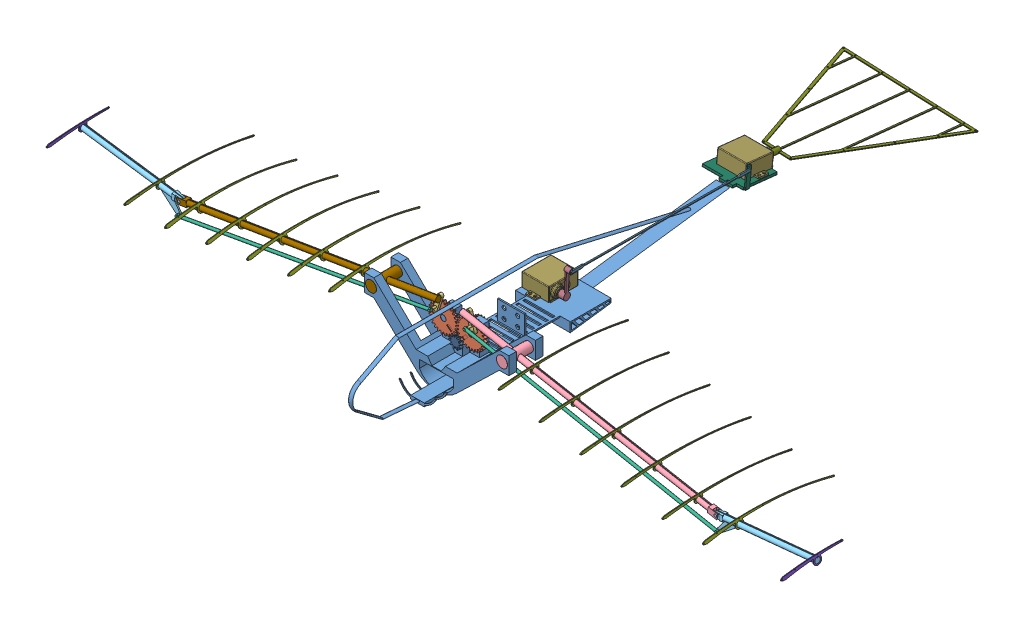
SolidWorks assembly 仿生扑翼鸟, configuration 默认. Lengths in mm.
Overall size (541.74 54.34 414.7).
33 component instances, 16 part files, 88 mates.
Components (placement in the parent):
- 驱干-1: 驱干 [默认] at origin size (106 50.33 280.63)
- 大齿轮-1: 大齿轮 [默认] at (10 25 8.1) x (0 0 1) z (-0.72003 0.693943 0) size (4.5 21.54 21.58)
- 连杆（齿轮-大翼）-1: 连杆（齿轮-大翼） [默认] at (13.8167 28.9602 10.6) x (0.265684 -0.96406 0) z (0 0 1) size (15 3 7.5)
- 大翼-右-1: 大翼-右 [默认] at (8.6616 40.8911 15.1) x (0.983461 -0.181119 0) z (0 0 1) size (192.4 8 25.2)
- 小翼-1: 小翼 [默认] at (269.4548 13.4698 15.1) x (0.995238 0.09747 0) z (0 0 1) size (75.4 13.5 4)
- 小翼连接件-1: 小翼连接件 [默认] at (197.379 -3.6369 17.6) x (-0.981244 0.192772 0) z (0 0 1) size (190 2 3)
- 大叶片-1: 大叶片 [默认] at (62.3222 32.7373 40.1) x (0 0 -1) z (0.983461 -0.181119 0) size (96.21 9.07 0.5)
- 大叶片-2: 大叶片 [默认] at (92.3178 27.2132 40.1) x (0 0 -1) z (0.983461 -0.181119 0) size (96.21 9.07 0.5)
- 大叶片-3: 大叶片 [默认] at (122.3134 21.689 40.1) x (0 0 -1) z (0.983461 -0.181119 0) size (96.21 9.07 0.5)
- 大叶片-4: 大叶片 [默认] at (152.3089 16.1649 40.1) x (0 0 -1) z (0.983461 -0.181119 0) size (96.21 9.07 0.5)
- 大叶片-6: 大叶片 [默认] at (182.3045 10.6408 40.1) x (0 0 -1) z (0.983461 -0.181119 0) size (96.21 9.07 0.5)
- 大叶片-9: 大叶片 [默认] at (211.8141 9.5328 40.1) x (0 0 -1) z (0.995238 0.09747 0) size (96.21 9.07 0.5)
- 小叶片-1: 小叶片 [默认] at (269.0403 15.1373 40.1) x (0 0 -1) z (0.995238 0.09747 0) size (45.94 7.58 0.6)
- 大翼-左-1: 大翼-左 [默认] at (-8.5358 40.1717 15.1) x (0.986604 0.163134 0) z (0 0 1) size (192.4 8 25.2)
- 大齿轮-2: 大齿轮 [默认] at (-10 25 8.1) x (0 0 1) z (-0.627917 -0.77828 0) size (4.5 21.54 21.58)
- 连杆（齿轮-大翼）-2: 连杆（齿轮-大翼） [默认] at (-14.2805 28.4535 10.6) x (-0.314291 -0.949327 0) z (0 0 1) size (15 3 7.5)
- 小翼-2: 小翼 [默认] at (-269.5532 19.3224 15.1) x (-0.990119 0.140232 0) z (0 0 -1) size (75.4 13.5 4)
- 小翼连接件-2: 小翼连接件 [默认] at (-198.2808 -0.8718 17.6) x (0.984554 0.175081 0) z (0 0 1) size (190 2 3)
- 大叶片-10: 大叶片 [默认] at (-62.3364 32.9989 40.1) x (0 0 -1) z (0.986604 0.163134 0) size (96.21 9.07 0.5)
- 大叶片-11: 大叶片 [默认] at (-92.4279 28.0233 40.1) x (0 0 -1) z (0.986604 0.163134 0) size (96.21 9.07 0.5)
- 大叶片-12: 大叶片 [默认] at (-122.5193 23.0477 40.1) x (0 0 -1) z (0.986604 0.163134 0) size (96.21 9.07 0.5)
- 大叶片-13: 大叶片 [默认] at (-152.6107 18.0721 40.1) x (0 0 -1) z (0.986604 0.163134 0) size (96.21 9.07 0.5)
- 大叶片-14: 大叶片 [默认] at (-182.7021 13.0965 40.1) x (0 0 -1) z (0.986604 0.163134 0) size (96.21 9.07 0.5)
- 大叶片-16: 大叶片 [默认] at (-212.1355 12.9072 40.1) x (0 0 -1) z (0.990119 -0.140232 0) size (96.21 9.07 0.5)
- 小叶片-2: 小叶片 [默认] at (-269.0673 20.9706 40.1) x (0 0 -1) z (0.990119 -0.140232 0) size (45.94 7.58 0.6)
- 小齿轮-1: 小齿轮 [默认] at (-1.4647 14 8.1) x (0 0 1) z (-0.996806 -0.079858 0) size (20 9.19 9.6)
- 中齿轮-1: 中齿轮 [默认] at (-1.4647 14 -9.9) x (0 0 1) z (0.760364 -0.649497 0) size (1.6 13.95 13.95)
- 伺服电机-1: 伺服电机 [Default] at (-9.8746 6.0912 -68.0005) x (1 0 0) z (0 1 0) size (27.51 28.79 10)
- 电机连杆-1: 电机连杆 [默认] at (6.8314 11.0912 -62.7894) x (0 -0.03758 -0.999294) z (1 0 0) size (5 21.3 7.2)
- 电机连接件-1: 电机连接件 [默认] at (11.3314 28.0792 -63.4283) x (0 -0.004012 -0.999992) z (-1 0 0) size (132.5 2.5 1.5)
- 私服电机安装版-1: 私服电机安装版 [默认] at (-5.17 14.5563 -202.3158) x (0 -0.10462 -0.994512) z (1 0 0) size (29.42 15 31)
- 伺服电机-2: 伺服电机 [Default] at (-5.1705 16.1974 -205.8322) x (0 -0.10462 -0.994512) z (0 0.994512 -0.10462) size (27.51 28.79 10)
- 尾巴-1: 尾巴 [默认] at (0.0406 19.3385 -223.7653) x (0 -0.10462 -0.994512) z (-0.037242 -0.993822 0.104548) size (104.44 99.53 4)
Mates (geometry in assembly coordinates):
- 同心1: concentric aligned: cylinder of 驱干-1 through (10 25 10) axis (0 0 -1) radius 2; cylinder of 大齿轮-1 through (10 25 58.1001) axis (0 0 -1) radius 2
- 距离1: distance = 0.1 mm aligned: plane of 驱干-1 through (10 25 10) normal (0 0 1); plane of 大齿轮-1 through (10 25 10.1) normal (0 0 1)
- 同心2: concentric aligned: cylinder of 大齿轮-1 through (13.8167 28.9602 12.6) axis (0 0 -1) radius 1; cylinder of 连杆（齿轮-大翼）-1 through (13.8167 28.9602 12.6) axis (0 0 -1) radius 1
- 重合2: coincident anti-aligned: plane of 大齿轮-1 through (10 25 10.1) normal (0 0 1); plane of 连杆（齿轮-大翼）-1 through (13.8167 28.9602 10.1) normal (0 0 -1)
- 同心3: concentric anti-aligned: cylinder of 连杆（齿轮-大翼）-1 through (10.6285 40.5289 12.6) axis (0 0 -1) radius 1; cylinder of 大翼-右-1 through (10.6285 40.5289 10.6) axis (0 0 1) radius 1
- 同心4: concentric aligned: cylinder of 驱干-1 through (48 33.6464 0) axis (0 0 1) radius 3.5; cylinder of 大翼-右-1 through (48 33.6464 0) axis (0 0 1) radius 3.5
- 重合3: coincident anti-aligned: plane of 驱干-1 through (0 12 25) normal (0 0 1); plane of 大翼-右-1 through (48 33.6464 25) normal (0 0 -1)
- 同心5: concentric anti-aligned: cylinder of 大翼-右-1 through (196.4043 6.3155 13.1) axis (0 0 1) radius 1; cylinder of 小翼-1 through (196.4043 6.3155 17.1) axis (0 0 -1) radius 1
- 重合4: coincident aligned: plane of 大翼-右-1 through (198.2417 8.0108 17.1) normal (0 0 1); plane of 小翼-1 through (196.4043 6.3155 17.1) normal (0 0 1)
- 同心6: concentric anti-aligned: cylinder of 连杆（齿轮-大翼）-1 through (12.8071 32.6236 17.6) axis (0 0 -1) radius 0.7; cylinder of 小翼连接件-1 through (12.8071 32.6236 14.6) axis (0 0 1) radius 0.7
- 重合5: coincident anti-aligned: plane of 连杆（齿轮-大翼）-1 through (12.8071 32.6236 15.6) normal (0 0 1); plane of 小翼连接件-1 through (12.8071 32.6236 15.6) normal (0 0 -1)
- 同心7: concentric anti-aligned: cylinder of 小翼-1 through (197.379 -3.6369 15.6) axis (0 0 -1) radius 1; cylinder of 小翼连接件-1 through (197.379 -3.6369 14.6) axis (0 0 1) radius 1
- 同心8: concentric aligned: cylinder of 大翼-右-1 through (197.8795 6.0438 15.1) axis (-0.983461 0.181119 0) radius 2; cylinder of 大叶片-1 through (62.2602 31.0201 15.1) axis (-0.983461 0.181119 0) radius 2
- 重合6: coincident anti-aligned: plane of 大翼-右-1 through (62.0401 32.5859 14.8) normal (0.983461 -0.181119 0); plane of 大叶片-1 through (61.8002 31.2831 41.8119) normal (-0.983461 0.181119 0)
- 重合7: coincident anti-aligned: plane of 大翼-右-1 through (62.0401 32.5859 15.4) normal (0 0 -1); plane of 大叶片-1 through (62.6183 32.9648 15.4) normal (0 0 1)
- 同心9: concentric aligned: cylinder of 大翼-右-1 through (197.8795 6.0438 15.1) axis (-0.983461 0.181119 0) radius 2; cylinder of 大叶片-2 through (92.2558 25.496 15.1) axis (-0.983461 0.181119 0) radius 2
- 重合8: coincident anti-aligned: plane of 大翼-右-1 through (62.0401 32.5859 15.4) normal (0 0 -1); plane of 大叶片-2 through (92.6139 27.4407 15.4) normal (0 0 1)
- 同心10: concentric aligned: cylinder of 大翼-右-1 through (197.8795 6.0438 15.1) axis (-0.983461 0.181119 0) radius 2; cylinder of 大叶片-3 through (122.2513 19.9719 15.1) axis (-0.983461 0.181119 0) radius 2
- 重合9: coincident anti-aligned: plane of 大翼-右-1 through (62.0401 32.5859 15.4) normal (0 0 -1); plane of 大叶片-3 through (122.6095 21.9165 15.4) normal (0 0 1)
- 同心11: concentric aligned: cylinder of 大翼-右-1 through (197.8795 6.0438 15.1) axis (-0.983461 0.181119 0) radius 2; cylinder of 大叶片-4 through (152.2469 14.4478 15.1) axis (-0.983461 0.181119 0) radius 2
- 重合10: coincident anti-aligned: plane of 大翼-右-1 through (62.0401 32.5859 15.4) normal (0 0 -1); plane of 大叶片-4 through (152.605 16.3924 15.4) normal (0 0 1)
- 距离2: distance = 30 mm anti-aligned: plane of 大叶片-1 through (62.2919 31.1925 41.8119) normal (0.983461 -0.181119 0); plane of 大叶片-2 through (91.7958 25.7589 41.8119) normal (-0.983461 0.181119 0)
- 距离3: distance = 30 mm anti-aligned: plane of 大叶片-2 through (92.2875 25.6684 41.8119) normal (0.983461 -0.181119 0); plane of 大叶片-3 through (121.7913 20.2348 41.8119) normal (-0.983461 0.181119 0)
- 距离4: distance = 30 mm anti-aligned: plane of 大叶片-3 through (122.2831 20.1442 41.8119) normal (0.983461 -0.181119 0); plane of 大叶片-4 through (151.7869 14.7107 41.8119) normal (-0.983461 0.181119 0)
- 同心13: concentric aligned: cylinder of 大翼-右-1 through (197.8795 6.0438 15.1) axis (-0.983461 0.181119 0) radius 2; cylinder of 大叶片-6 through (182.2425 8.9236 15.1) axis (-0.983461 0.181119 0) radius 2
- 重合12: coincident anti-aligned: plane of 大翼-右-1 through (62.0401 32.5859 15.4) normal (0 0 -1); plane of 大叶片-6 through (182.6006 10.8683 15.4) normal (0 0 1)
- 距离7: distance = 30 mm anti-aligned: plane of 大叶片-4 through (152.2786 14.6201 41.8119) normal (0.983461 -0.181119 0); plane of 大叶片-6 through (181.7825 9.1865 41.8119) normal (-0.983461 0.181119 0)
- 同心16: concentric anti-aligned: cylinder of 小翼-1 through (201.7786 6.8418 15.1) axis (0.995238 0.09747 0) radius 2; cylinder of 大叶片-9 through (212.2286 7.8653 15.1) axis (-0.995238 -0.09747 0) radius 2
- 重合13: coincident anti-aligned: plane of 小翼-1 through (194.2676 7.6134 15.4) normal (0 0 -1); plane of 大叶片-9 through (212.0359 9.8332 15.4) normal (0 0 1)
- 距离8: distance = 10 mm anti-aligned: plane of 小翼-1 through (201.5836 8.8323 17.1) normal (0.995238 0.09747 0); plane of 大叶片-9 through (211.7139 7.991 41.8119) normal (-0.995238 -0.09747 0)
- 同心17: concentric anti-aligned: cylinder of 小翼-1 through (201.7786 6.8418 15.1) axis (0.995238 0.09747 0) radius 2; cylinder of 小叶片-1 through (269.4548 13.4698 15.1) axis (-0.995238 -0.09747 0) radius 2
- 重合14: coincident anti-aligned: plane of 小翼-1 through (194.2676 7.6134 15.4) normal (0 0 -1); plane of 小叶片-1 through (269.2621 15.4378 15.4) normal (0 0 1)
- 重合15: coincident aligned: plane of 小翼-1 through (269.4548 13.4698 15.1) normal (0.995238 0.09747 0); plane of 小叶片-1 through (269.4377 13.6442 41.8119) normal (0.995238 0.09747 0)
- 同心18: concentric aligned: cylinder of 驱干-1 through (-10 25 10) axis (0 0 -1) radius 2; cylinder of 大齿轮-2 through (-10 25 58.1001) axis (0 0 -1) radius 2
- 距离9: distance = 0.1 mm aligned: plane of 驱干-1 through (-10 25 10) normal (0 0 1); plane of 大齿轮-2 through (-10 25 10.1) normal (0 0 1)
- 同心19: concentric aligned: cylinder of 大齿轮-2 through (-14.2805 28.4535 12.6) axis (0 0 -1) radius 1; cylinder of 连杆（齿轮-大翼）-2 through (-14.2805 28.4535 12.6) axis (0 0 -1) radius 1
- 重合16: coincident aligned: plane of 大齿轮-2 through (-14.2805 28.4535 12.6) normal (0 0 1); plane of 连杆（齿轮-大翼）-2 through (-14.2805 28.4535 12.6) normal (0 0 1)
- 同心20: concentric anti-aligned: cylinder of 大翼-左-1 through (-10.5091 39.8455 10.6) axis (0 0 1) radius 1; cylinder of 连杆（齿轮-大翼）-2 through (-10.5091 39.8455 12.6) axis (0 0 -1) radius 1
- 同心21: concentric aligned: cylinder of 驱干-1 through (-48 33.6464 0) axis (0 0 1) radius 3.5; cylinder of 大翼-左-1 through (-48 33.6464 0) axis (0 0 1) radius 3.5
- 重合17: coincident anti-aligned: plane of 驱干-1 through (0 12 25) normal (0 0 1); plane of 大翼-左-1 through (-48 33.6464 25) normal (0 0 -1)
- 同心22: concentric aligned: cylinder of 大翼-左-1 through (-196.8785 9.0294 13.1) axis (0 0 1) radius 1; cylinder of 小翼-2 through (-196.8785 9.0294 13.1) axis (0 0 1) radius 1
- 重合18: coincident aligned: plane of 大翼-左-1 through (-198.6847 10.7579 17.1) normal (0 0 1); plane of 小翼-2 through (-196.8785 9.0294 17.1) normal (0 0 1)
- 同心23: concentric anti-aligned: cylinder of 连杆（齿轮-大翼）-2 through (-13.0862 32.061 17.6) axis (0 0 -1) radius 0.7; cylinder of 小翼连接件-2 through (-13.0862 32.061 14.6) axis (0 0 1) radius 0.7
- 重合19: coincident anti-aligned: plane of 连杆（齿轮-大翼）-2 through (-13.0862 32.061 15.6) normal (0 0 1); plane of 小翼连接件-2 through (-13.0862 32.061 15.6) normal (0 0 -1)
- 同心24: concentric aligned: cylinder of 小翼-2 through (-198.2808 -0.8718 14.6) axis (0 0 1) radius 1; cylinder of 小翼连接件-2 through (-198.2808 -0.8718 14.6) axis (0 0 1) radius 1
- 同心25: concentric anti-aligned: cylinder of 大翼-左-1 through (-198.3584 8.7847 15.1) axis (0.986604 0.163134 0) radius 2; cylinder of 大叶片-10 through (-61.8125 31.3625 15.1) axis (-0.986604 -0.163134 0) radius 2
- 重合20: coincident anti-aligned: plane of 大翼-左-1 through (-62.0572 32.8424 14.8) normal (-0.986604 -0.163134 0); plane of 大叶片-10 through (-61.841 31.5354 41.8119) normal (0.986604 0.163134 0)
- 重合21: coincident anti-aligned: plane of 大翼-左-1 through (-62.0572 32.8424 15.4) normal (0 0 -1); plane of 大叶片-10 through (-62.135 33.3134 15.4) normal (0 0 1)
- 同心26: concentric anti-aligned: cylinder of 大翼-左-1 through (-198.3584 8.7847 15.1) axis (0.986604 0.163134 0) radius 2; cylinder of 大叶片-11 through (-91.9039 26.3869 15.1) axis (-0.986604 -0.163134 0) radius 2
- 重合22: coincident anti-aligned: plane of 大翼-左-1 through (-62.0572 32.8424 14.8) normal (0 0 1); plane of 大叶片-11 through (-92.2264 28.3378 14.8) normal (0 0 -1)
- 距离10: distance = 30 mm anti-aligned: plane of 大叶片-10 through (-62.3343 31.4538 41.8119) normal (-0.986604 -0.163134 0); plane of 大叶片-11 through (-91.9325 26.5598 41.8119) normal (0.986604 0.163134 0)
- 同心27: concentric anti-aligned: cylinder of 大翼-左-1 through (-198.3584 8.7847 15.1) axis (0.986604 0.163134 0) radius 2; cylinder of 大叶片-12 through (-121.9953 21.4113 15.1) axis (-0.986604 -0.163134 0) radius 2
- 重合23: coincident anti-aligned: plane of 大翼-左-1 through (-62.0572 32.8424 14.8) normal (0 0 1); plane of 大叶片-12 through (-122.3179 23.3622 14.8) normal (0 0 -1)
- 距离11: distance = 30 mm anti-aligned: plane of 大叶片-11 through (-92.4258 26.4782 41.8119) normal (-0.986604 -0.163134 0); plane of 大叶片-12 through (-122.0239 21.5842 41.8119) normal (0.986604 0.163134 0)
- 同心28: concentric anti-aligned: cylinder of 大翼-左-1 through (-198.3584 8.7847 15.1) axis (0.986604 0.163134 0) radius 2; cylinder of 大叶片-13 through (-152.0867 16.4357 15.1) axis (-0.986604 -0.163134 0) radius 2
- 重合24: coincident anti-aligned: plane of 大翼-左-1 through (-62.0572 32.8424 14.8) normal (0 0 1); plane of 大叶片-13 through (-152.4093 18.3866 14.8) normal (0 0 -1)
- 距离12: distance = 30 mm anti-aligned: plane of 大叶片-12 through (-122.5172 21.5026 41.8119) normal (-0.986604 -0.163134 0); plane of 大叶片-13 through (-152.1153 16.6086 41.8119) normal (0.986604 0.163134 0)
- 同心29: concentric anti-aligned: cylinder of 大翼-左-1 through (-198.3584 8.7847 15.1) axis (0.986604 0.163134 0) radius 2; cylinder of 大叶片-14 through (-182.1781 11.4601 15.1) axis (-0.986604 -0.163134 0) radius 2
- 重合25: coincident anti-aligned: plane of 大翼-左-1 through (-62.0572 32.8424 14.8) normal (0 0 1); plane of 大叶片-14 through (-182.5007 13.411 14.8) normal (0 0 -1)
- 距离13: distance = 30 mm anti-aligned: plane of 大叶片-13 through (-152.6086 16.527 41.8119) normal (-0.986604 -0.163134 0); plane of 大叶片-14 through (-182.2067 11.633 41.8119) normal (0.986604 0.163134 0)
- 同心31: concentric aligned: cylinder of 小翼-2 through (-202.2252 9.7866 15.1) axis (-0.990119 0.140232 0) radius 2; cylinder of 大叶片-16 through (-212.1264 11.189 15.1) axis (-0.990119 0.140232 0) radius 2
- 重合27: coincident anti-aligned: plane of 小翼-2 through (-194.6879 10.2341 14.8) normal (0 0 1); plane of 大叶片-16 through (-211.8491 13.1468 14.8) normal (0 0 -1)
- 距离14: distance = 10 mm anti-aligned: plane of 小翼-2 through (-201.9447 11.7669 13.1) normal (-0.990119 0.140232 0); plane of 大叶片-16 through (-212.1018 11.3625 41.8119) normal (0.990119 -0.140232 0)
- 同心32: concentric aligned: cylinder of 小翼-2 through (-202.2252 9.7866 15.1) axis (-0.990119 0.140232 0) radius 2; cylinder of 小叶片-2 through (-269.0582 19.2523 15.1) axis (-0.990119 0.140232 0) radius 2
- 重合28: coincident aligned: plane of 小翼-2 through (-269.5532 19.3224 15.1) normal (-0.990119 0.140232 0); plane of 小叶片-2 through (-269.5287 19.4959 41.8119) normal (-0.990119 0.140232 0)
- 重合29: coincident anti-aligned: plane of 小翼-2 through (-194.6879 10.2341 15.4) normal (0 0 -1); plane of 小叶片-2 through (-268.7809 21.2101 15.4) normal (0 0 1)
- 同心33: concentric aligned: cylinder of 驱干-1 through (-1.4647 14 7) axis (0 0 1) radius 2; cylinder of 小齿轮-1 through (-1.4647 14 -9.9) axis (0 0 1) radius 2
- 重合30: coincident aligned: plane of 大齿轮-2 through (-10 25 10.1) normal (0 0 1); plane of 小齿轮-1 through (-1.4647 14 10.1) normal (0 0 1)
- 同心34: concentric aligned: cylinder of 小齿轮-1 through (-1.4647 14 -9.9) axis (0 0 1) radius 2; cylinder of 中齿轮-1 through (-1.4647 14 -18.3) axis (0 0 1) radius 2
- 重合31: coincident aligned: plane of 小齿轮-1 through (-1.4647 14 -9.9) normal (0 0 -1); plane of 中齿轮-1 through (-1.4647 14 -9.9) normal (0 0 -1)
- 重合32: coincident anti-aligned: plane of 驱干-1 through (20 6.0912 -53) normal (0 1 0); plane of 伺服电机-1 through (-9.8746 6.0912 -68.0005) normal (0 -1 0)
- 同心35: concentric anti-aligned: cylinder of 驱干-1 through (-8.05 -9 -80.57) axis (0 1 0) radius 1; cylinder of 伺服电机-1 through (-8.05 7.0912 -80.571) axis (0 -1 0) radius 1
- 同心36: concentric anti-aligned: cylinder of 驱干-1 through (-8.05 -9 -55.43) axis (0 1 0) radius 1; cylinder of 伺服电机-1 through (-8.05 7.0912 -55.43) axis (0 -1 0) radius 1
- 同心37: concentric aligned: cylinder of 伺服电机-1 through (7.6314 11.0912 -62.7894) axis (-1 0 0) radius 1.9; cylinder of 电机连杆-1 through (7.6314 11.0912 -62.7894) axis (-1 0 0) radius 1.9
- 重合34: coincident anti-aligned: plane of 伺服电机-1 through (7.6314 11.0912 -62.7894) normal (1 0 0); plane of 电机连杆-1 through (7.6314 11.0912 -62.7894) normal (-1 0 0)
- 同心38: concentric aligned: cylinder of 电机连杆-1 through (9.8314 28.0792 -63.4283) axis (1 0 0) radius 1.25; cylinder of 电机连接件-1 through (10.8314 28.0792 -63.4283) axis (1 0 0) radius 1.25
- 重合35: coincident anti-aligned: plane of 电机连杆-1 through (9.8314 28.0792 -63.4283) normal (1 0 0); plane of 电机连接件-1 through (9.8314 28.0792 -63.4283) normal (-1 0 0)
- 同心39: concentric anti-aligned: cylinder of 驱干-1 through (1 17.0678 -188) axis (-1 0 0) radius 0.6; cylinder of 私服电机安装版-1 through (-2 17.0678 -188) axis (1 0 0) radius 0.6
- 宽度1: width anti-aligned: plane of 驱干-1 through (-0.5 17.0678 -188.25) normal (-1 0 0); plane of 驱干-1 through (0.5 17.0678 -188.25) normal (1 0 0); plane of 私服电机安装版-1 through (-0.5 18.1669 -187.1101) normal (1 0 0); plane of 私服电机安装版-1 through (0.5 18.0437 -186.9764) normal (-1 0 0)
- 同心40: concentric anti-aligned: cylinder of 电机连接件-1 through (10.8314 27.5576 -193.4272) axis (1 0 0) radius 1.25; cylinder of 私服电机安装版-1 through (10.83 27.5576 -193.4272) axis (-1 0 0) radius 1.25
- 重合37: coincident anti-aligned: plane of 私服电机安装版-1 through (-5.17 16.5453 -202.525) normal (0 0.994512 -0.10462); plane of 伺服电机-2 through (-5.1705 16.1974 -205.8322) normal (0 -0.994512 0.10462)
- 同心41: concentric aligned: cylinder of 私服电机安装版-1 through (7.4 16.3884 -204.0168) axis (0 -0.994512 0.10462) radius 1; cylinder of 伺服电机-2 through (7.4 17.3828 -204.1223) axis (0 -0.994512 0.10462) radius 1
- 同心42: concentric aligned: cylinder of 私服电机安装版-1 through (7.4 16.0065 -207.6468) axis (0 -0.994512 0.10462) radius 1; cylinder of 伺服电机-2 through (7.4 17.001 -207.7514) axis (0 -0.994512 0.10462) radius 1
- 重合38: coincident anti-aligned: plane of 伺服电机-2 through (0.0406 19.3385 -223.7653) normal (0 -0.10462 -0.994512); plane of 尾巴-1 through (-10.3617 22.8353 -224.1331) normal (0 0.10462 0.994512)
- 齿轮配合1: gear = 25 : 25 mm: circle of 大齿轮-2; circle of 大齿轮-1
- 齿轮配合2: gear = 25 : 10 mm: circle of 小齿轮-1; circle of 大齿轮-2
- 锁定1: lock: unknown of 小齿轮-1; unknown of 中齿轮-1
- 同心43: concentric anti-aligned: cylinder of 伺服电机-2 through (0.0406 19.3385 -223.7653) axis (0 0.10462 0.994512) radius 1.9; cylinder of 尾巴-1 through (0.1403 22.6949 -224.1183) axis (0 -0.10462 -0.994512) radius 1.9
